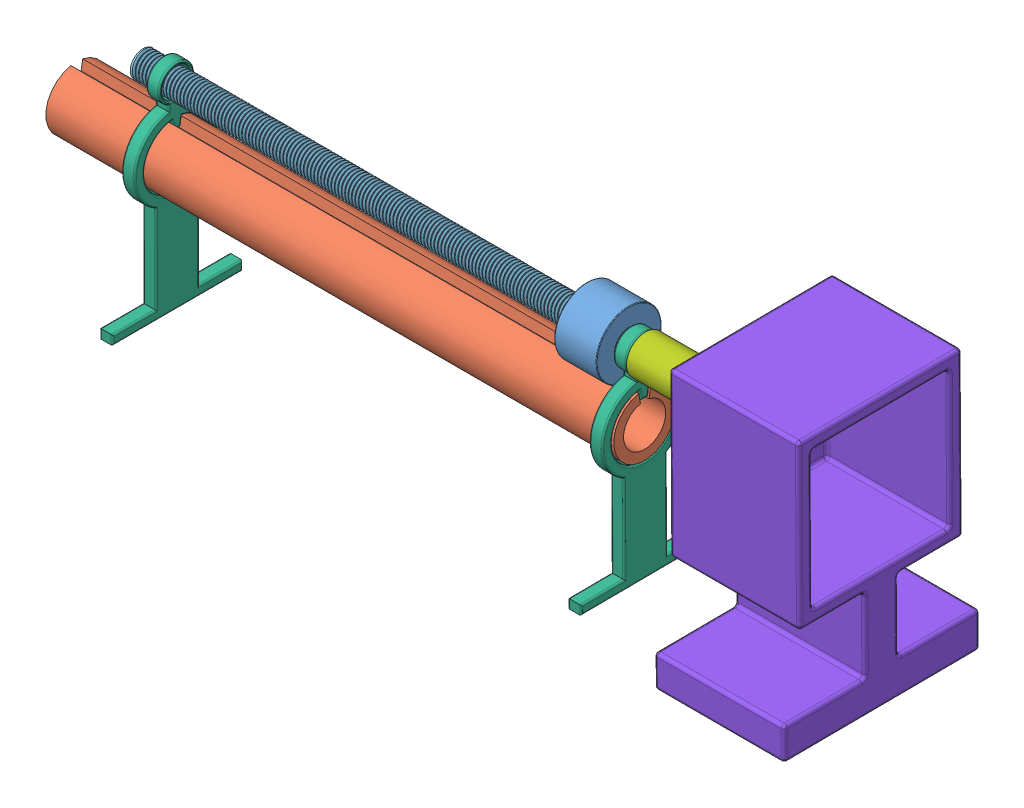
SolidWorks assembly MS-A-0015-Leadscrew Loading Mechanism, configuration Default. Lengths in mm.
Overall size (250.72 85.78 60.85).
13 component instances, 8 part files, 18 mates.
Components (placement in the parent):
- MS-P-0062- Pusher Leadscrew-1: MS-P-0062- Pusher Leadscrew [Default] at (-14.8933 1.4635 -1.8038) x (1 0 0) z (0 -0.012294 0.999924) size (13.03 28.45 20)
- MS-P-0063 Launching tube-1: MS-P-0063 Launching tube [Default] at (0 2.1827 -1.478) x (0 0.005105 0.999987) z (0 -0.999987 0.005105) size (19 175.02 18.82)
- MS-A-0015-Flywheel Torpedo-1: MS-A-0015-Flywheel Torpedo [Default] at (-54.1613 -27.376 11.943) x (0 0 -1) z (0 1 0) size (15.8 80 15.8)
  - MS-P-0052- Flywheel Torpedo Body-1: MS-P-0052- Flywheel Torpedo Body [Default] at (13.4209 3.732 29.5587) size (12 40 12)
  - MS-P-0051- Flywheel Torpedo Fins-1: MS-P-0051- Flywheel Torpedo Fins [Default] at (13.4209 11.732 29.5587) x (-0.916326 0 0.400432) z (0.400432 0 0.916326) size (12 48 12)
- MS-A-0015-Flywheel Torpedo-2: MS-A-0015-Flywheel Torpedo [Default] at (-134.1613 -27.376 11.943) x (0 0 -1) z (0 1 0) size (15.8 80 15.8)
  - MS-P-0052- Flywheel Torpedo Body-1: MS-P-0052- Flywheel Torpedo Body [Default] at (13.4209 3.732 29.5587) size (12 40 12)
  - MS-P-0051- Flywheel Torpedo Fins-1: MS-P-0051- Flywheel Torpedo Fins [Default] at (13.4209 11.732 29.5587) x (-0.916326 0 0.400432) z (0.400432 0 0.916326) size (12 48 12)
- leadscrew-1: leadscrew [Default] at (15.3284 21.3389 -1.5861) x (0 0.628931 0.777461) z (-1 0 0) size (7.94 9.17 170)
- holder-1: holder [Default] at (-4.1288 2.1369 -1.7739) x (0 0.006664 -0.999978) z (1 0 0) size (40 65.75 4.09)
- holder-2: holder [Default] at (-148.2457 2.1353 -1.7737) x (0 0.001367 -0.999999) z (1 0 0) size (40 65.75 4.09)
- motor connector-1: motor connector [Default] at (17.8284 21.3392 -1.4585) x (0 0.998443 -0.055773) z (0 -0.055773 -0.998443) size (12.15 32.5 12.15)
- motor mount-1: motor mount [Default] at (32.8284 0.0488 19.5501) x (0 0.006664 -0.999978) z (1 0 0) size (60.3 83.29 40)
Mates (geometry in assembly coordinates):
- Parallel2: parallel aligned: line of stopper thing-1 through (-17.6933 11.496 -3.3517) axis (1 0 0); line of tube-1 through (-175.02 11.496 -3.3517) axis (1 0 0)
- Concentric1: concentric aligned: cylinder of tube-1 through (-175.02 2.1827 -1.478) axis (1 0 0) radius 6.5; cylinder of MS-A-0015-Flywheel Torpedo-1/MS-P-0052- Flywheel Torpedo Body-1 through (-97.8933 2.1827 -1.478) axis (1 0 0) radius 6
- Coincident4: coincident anti-aligned: plane of stopper thing-1 through (-17.8933 1.4635 -1.8038) normal (-1 0 0); plane of MS-A-0015-Flywheel Torpedo-1/MS-P-0051- Flywheel Torpedo Fins-1 through (-17.8933 2.1827 -1.478) normal (1 0 0)
- Parallel1: parallel aligned: line of stopper thing-1 through (-5.0933 11.4642 -0.008) axis (-1 0 0); line of tube-1 through (0 11.5147 0.3006) axis (-1 0 0)
- Coincident6: coincident aligned: line of stopper thing-1 through (-17.6933 11.496 -3.3517) axis (1 0 0); line of tube-1 through (-175.02 11.496 -3.3517) axis (1 0 0)
- Parallel3: parallel anti-aligned: plane of stopper thing-1 through (-17.8933 6.4521 -0.8424) normal (0 -0.164197 0.986428); plane of tube-1 through (0 7.282 -0.404) normal (0 0.164197 -0.986428)
- Coincident9: coincident anti-aligned: plane of MS-A-0015-Flywheel Torpedo-1/MS-P-0052- Flywheel Torpedo Body-1 through (-97.8933 2.1827 -1.478) normal (-1 0 0); plane of MS-A-0015-Flywheel Torpedo-2/MS-P-0051- Flywheel Torpedo Fins-1 through (-97.8933 2.1827 -1.478) normal (1 0 0)
- Concentric2: concentric aligned: cylinder of tube-1 through (-175.02 2.1827 -1.478) axis (1 0 0) radius 6.5; cylinder of MS-A-0015-Flywheel Torpedo-2/MS-P-0052- Flywheel Torpedo Body-1 through (-177.8933 2.1827 -1.478) axis (1 0 0) radius 6
- Coincident10: coincident aligned: plane of tube-1 through (0 2.1827 -1.478) normal (1 0 0)
- Concentric3: concentric aligned: circle of stopper thing-1; circle of screw-1
- Parallel5: parallel anti-aligned: plane of tube-1 through (-175.02 2.1827 -1.478) normal (-1 0 0); plane of holder-1 through (-0.1288 2.1369 -1.7739) normal (1 0 0)
- Concentric6: concentric anti-aligned: cylinder of tube-1 through (-175.02 2.1827 -1.478) axis (1 0 0) radius 9.5; cylinder of holder-1 through (-0.1288 2.1827 -1.478) axis (-1 0 0) radius 9.8777
- Concentric8: concentric anti-aligned: circle of holder-1; circle of motor mount-1
- Parallel7: parallel anti-aligned: line of holder-1 through (-0.1288 -38.5881 17.4496) axis (0 0.006664 -0.999978); cylinder of motor mount-1 through (71.8284 -35.9418 19.3103) axis (0 -0.006664 0.999978) radius 1
- Concentric11: concentric anti-aligned: circle of holder-1; circle of motor connector-1
- Coincident11: coincident anti-aligned: plane of screw-1 through (15.3284 21.3389 -1.5861) normal (1 0 0); plane of motor connector-1 through (15.3284 21.3392 -1.4585) normal (-1 0 0)
- Coincident12: coincident anti-aligned: plane of motor connector-1 through (32.8284 21.3392 -1.4585) normal (1 0 0); plane of motor mount-1 through (32.8284 0.0488 19.5501) normal (-1 0 0)
- Screw1: screw = 1 anti-aligned: circle of MS-P-0062- Pusher Leadscrew-1
